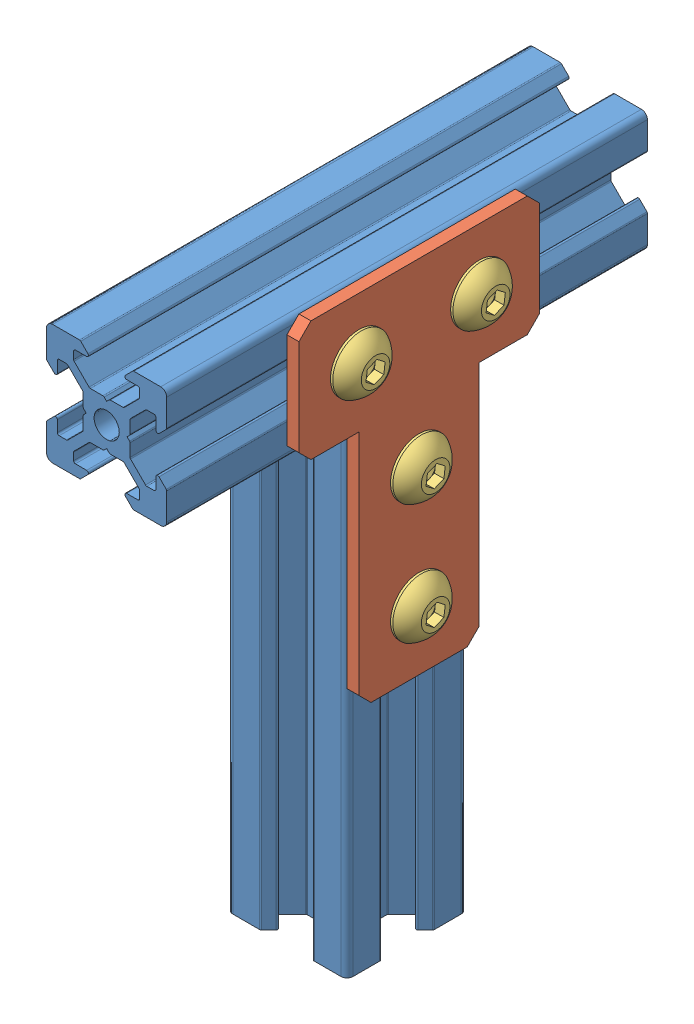
SolidWorks assembly Т-пластина 20 серия 2х3 4отв 40х60х2 СБ, configuration По умолчанию. Lengths in mm.
Overall size (24.75 100 80).
7 component instances, 3 part files, 14 mates.
Components (placement in the parent):
- 2020100-1: 2020100 [По умолчанию] at origin size (20 20 80)
- 2020100-2: 2020100 [По умолчанию] at (0 -90 40) x (1 0 0) z (0 1 0) size (20 20 80)
- Т-пластина 20 серия 2х3 4отв 40х60х2-1: Т-пластина 20 серия 2х3 4отв 40х60х2 [По умолчанию] at (10 -50 40) x (0 0 -1) z (0 -1 0) size (40 2 60)
- socket button head screw_iso-1: socket button head screw_iso [ISO 7380 - M5 x 10 - 10N] at (14.75 0 50) x (-1 0 0) z (0 0.924225 0.381849) size (12.75 9.5 9.5)
- socket button head screw_iso-2: socket button head screw_iso [ISO 7380 - M5 x 10 - 10N] at (14.75 0 30) x (-1 0 0) z (0 0.924225 0.381849) size (12.75 9.5 9.5)
- socket button head screw_iso-3: socket button head screw_iso [ISO 7380 - M5 x 10 - 10N] at (14.75 -20 40) x (-1 0 0) z (0 0.924225 0.381849) size (12.75 9.5 9.5)
- socket button head screw_iso-4: socket button head screw_iso [ISO 7380 - M5 x 10 - 10N] at (14.75 -40 40) x (-1 0 0) z (0 0.924225 0.381849) size (12.75 9.5 9.5)
Mates (geometry in assembly coordinates):
- Совпадение1: coincident aligned: plane of 2020100-1 through (10 -10 80) normal (1 0 0); plane of 2020100-2 through (10 -10 30) normal (1 0 0)
- Совпадение2: coincident anti-aligned: plane of 2020100-1 through (10 -10 80) normal (0 -1 0); plane of 2020100-2 through (0 -10 40) normal (0 1 0)
- Расстояние1: distance = 30 mm aligned: plane of 2020100-2 through (-10 -10 50) normal (0 0 1); plane of 2020100-1 through (0 0 80) normal (0 0 1)
- Совпадение3: coincident anti-aligned: plane of 2020100-1 through (10 -10 80) normal (1 0 0); plane of Т-пластина 20 серия 2х3 4отв 40х60х2-1 through (10 -50 40) normal (-1 0 0)
- Совпадение4: coincident aligned: plane of 2020100-2 through (10 -10 30) normal (0 0 -1); plane of Т-пластина 20 серия 2х3 4отв 40х60х2-1 through (12 -10 30) normal (0 0 -1)
- Совпадение5: coincident aligned: plane of 2020100-1 through (10 10 80) normal (0 1 0); plane of Т-пластина 20 серия 2х3 4отв 40х60х2-1 through (12 10 60) normal (0 1 0)
- Концентричный1: concentric aligned: cylinder of Т-пластина 20 серия 2х3 4отв 40х60х2-1 through (12 0 50) axis (1 0 0) radius 2.75; cylinder of socket button head screw_iso-1 through (14.75 0 50) axis (1 0 0) radius 4.75
- Совпадение6: coincident anti-aligned: plane of Т-пластина 20 серия 2х3 4отв 40х60х2-1 through (12 -50 40) normal (1 0 0); plane of socket button head screw_iso-1 through (12 -0.9546 52.3106) normal (-1 0 0)
- Концентричный2: concentric aligned: cylinder of Т-пластина 20 серия 2х3 4отв 40х60х2-1 through (12 0 30) axis (1 0 0) radius 2.75; cylinder of socket button head screw_iso-2 through (14.75 0 30) axis (1 0 0) radius 4.75
- Совпадение7: coincident anti-aligned: plane of Т-пластина 20 серия 2х3 4отв 40х60х2-1 through (12 -50 40) normal (1 0 0); plane of socket button head screw_iso-2 through (12 -0.9546 32.3106) normal (-1 0 0)
- Концентричный3: concentric aligned: cylinder of Т-пластина 20 серия 2х3 4отв 40х60х2-1 through (12 -20 40) axis (1 0 0) radius 2.75; cylinder of socket button head screw_iso-3 through (14.75 -20 40) axis (1 0 0) radius 4.75
- Совпадение8: coincident anti-aligned: plane of Т-пластина 20 серия 2х3 4отв 40х60х2-1 through (12 -50 40) normal (1 0 0); plane of socket button head screw_iso-3 through (12 -20.9546 42.3106) normal (-1 0 0)
- Концентричный4: concentric aligned: cylinder of Т-пластина 20 серия 2х3 4отв 40х60х2-1 through (12 -40 40) axis (1 0 0) radius 2.75; cylinder of socket button head screw_iso-4 through (14.75 -40 40) axis (1 0 0) radius 4.75
- Совпадение9: coincident anti-aligned: plane of Т-пластина 20 серия 2х3 4отв 40х60х2-1 through (12 -50 40) normal (1 0 0); plane of socket button head screw_iso-4 through (12 -40.9546 42.3106) normal (-1 0 0)
